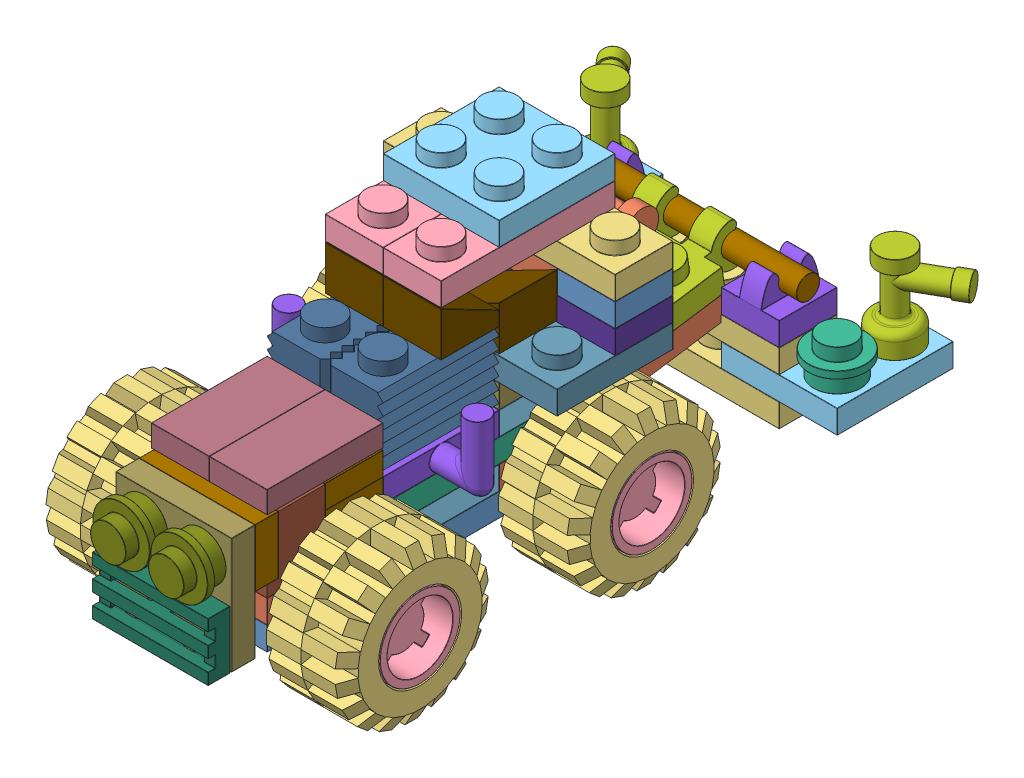
SolidWorks assembly Tractor, configuration Default. Lengths in mm.
Overall size (55.77 47.68 92.37).
59 component instances, 27 part files, 133 mates.
Components (placement in the parent):
- 379526-2: 379526 [Default] at (-1.8667 0.3637 29.8115) size (15.92 5.02 47.76)
- Wheel Assembly-3: Wheel Assembly [Default] at (5.4524 4.3288 25.4431) size (42 29.52 29.52)
  - 4211504-1: 4211504 [Default] at (-7.319 -0.7451 4.3684) size (27.68 6.09 15.92)
  - 4514560-1: 4514560 [Default] at (-18.469 0.3282 0.3884) x (1 0 0) z (0 -0.782052 0.623213) size (11.74 21 21)
  - 4514560-2: 4514560 [Default] at (11.791 0.3282 0.3884) size (11.74 21 21)
  - 4170457-1: 4170457 [Default] at (-12.499 0.3282 0.3884) x (0 1 0) z (0 0 1) size (11 11.84 11)
  - 4170457-2: 4170457 [Default] at (5.821 0.3282 0.3884) x (0 -1 0) z (0 0 1) size (11 11.84 11)
- Wheel Assembly-4: Wheel Assembly [Default] at (5.4524 4.3288 -6.3969) size (42 29.52 29.52)
  - 4211504-1: 4211504 [Default] at (-7.319 -0.7451 4.3684) size (27.68 6.09 15.92)
  - 4514560-1: 4514560 [Default] at (-18.469 0.3282 0.3884) x (1 0 0) z (0 -0.782052 0.623213) size (11.74 21 21)
  - 4514560-2: 4514560 [Default] at (11.791 0.3282 0.3884) size (11.74 21 21)
  - 4170457-1: 4170457 [Default] at (-12.499 0.3282 0.3884) x (0 1 0) z (0 0 1) size (11 11.84 11)
  - 4170457-2: 4170457 [Default] at (5.821 0.3282 0.3884) x (0 -1 0) z (0 0 1) size (11 11.84 11)
- 302224-4: 302224 [Default] at (-1.8667 3.5837 13.8915) size (15.92 5.02 15.92)
- 302024-2: 302024 [Default] at (6.0933 6.8037 21.8515) x (0 0 -1) z (1 0 0) size (31.84 5.02 15.92)
- 4519849-1: 4519849 [Default] at (6.0933 6.8037 -9.9885) x (-1 0 0) z (0 0 -1) size (15.92 6 12.56)
- 302224-5: 302224 [Default] at (-1.8667 10.0237 -2.0285) size (15.92 5.02 15.92)
- 4501109-1: 4501109 [Default] at (6.0933 10.0237 13.8915) x (0 0 -1) z (1 0 0) size (15.92 9.46 14.57)
- 4501109-2: 4501109 [Default] at (-1.8667 10.0237 5.9315) x (0 0 1) z (-1 0 0) size (15.92 9.46 14.57)
- 302326-5: 302326 [Default] at (-1.8667 10.0237 21.8515) size (15.92 5.02 7.96)
- 302326-6: 302326 [Default] at (-1.8667 13.2437 21.8515) size (15.92 5.02 7.96)
- 287724-3: 287724 [Default] at (6.0933 13.2437 13.8915) x (0 0 -1) z (1 0 0) size (15.92 11.5 7.96)
- 287724-4: 287724 [Default] at (-1.8667 13.2437 5.9315) x (0 0 1) z (-1 0 0) size (15.92 11.5 7.96)
- 407026-3: 407026 [Default] at (-1.8667 6.8037 29.8115) x (0 0 -1) z (1 0 0) size (7.96 11.34 7.96)
- 407026-4: 407026 [Default] at (6.0933 6.8037 29.8115) x (0 0 -1) z (1 0 0) size (7.96 11.34 7.96)
- 4211094-2: 4211094 [Default] at (-1.8667 13.2437 -2.0285) size (15.92 5.02 15.92)
- 302326-7: 302326 [Default] at (-1.8667 12.3637 32.2365) x (1 0 0) z (0 -1 0) size (15.92 5.02 7.96)
- 306924-3: 306924 [Default] at (-1.8667 16.4637 29.8115) x (0 0 -1) z (1 0 0) size (15.92 3.22 7.96)
- 306924-4: 306924 [Default] at (6.0933 16.4637 29.8115) x (0 0 -1) z (1 0 0) size (15.92 3.22 7.96)
- 4211065-2: 4211065 [Default] at (-9.8267 16.4637 -2.0285) size (31.84 5.02 15.92)
- 4211094-3: 4211094 [Default] at (-1.8667 4.4037 35.4565) x (1 0 0) z (0 -1 0) size (15.92 5.02 15.92)
- 4211350-3: 4211350 [Default] at (-1.8667 4.4037 38.6765) x (1 0 0) z (0 -1 0) size (15.92 3.22 7.96)
- 3005744-3: 3005744 [Default] at (-1.8667 12.3637 38.6765) x (1 0 0) z (0 -1 0) size (7.8 5.02 7.8)
- 3005744-4: 3005744 [Default] at (6.0933 12.3637 38.6765) x (1 0 0) z (0 -1 0) size (7.8 5.02 7.8)
- 371024-2: 371024 [Default] at (-9.8267 19.6837 -9.9885) size (31.84 5.02 7.96)
- 4244368-3: 4244368 [Default] at (-1.8667 19.6837 -2.0285) x (0 0 -1) z (1 0 0) size (7.96 6.27 7.96)
- 4244368-4: 4244368 [Default] at (6.0933 19.6837 -2.0285) x (0 0 1) z (-1 0 0) size (7.96 6.27 7.96)
- 3000841-1: 3000841 [Default] at (14.0533 22.9037 -9.9885) size (7.96 5.02 7.96)
- 3000841-2: 3000841 [Default] at (-9.8267 22.9037 -9.9885) size (7.96 5.02 7.96)
- 4244627-2: 4244627 [Default] at (6.0933 22.9037 -9.9885) x (-1 0 0) z (0 0 -1) size (15.92 5.02 13.96)
- 4211001-3: 4211001 [Default] at (-9.8267 26.1237 -9.9885) size (31.84 5.02 7.96)
- 4244368-5: 4244368 [Default] at (-1.8667 22.9437 5.9315) x (-1 0 0) z (0 0 -1) size (7.96 6.27 7.96)
- 4244368-6: 4244368 [Default] at (6.0933 22.9437 5.9315) x (-1 0 0) z (0 0 -1) size (7.96 6.27 7.96)
- 362324-2: 362324 [Default] at (-1.8667 29.3437 5.9315) x (0 0 -1) z (1 0 0) size (23.88 5.02 7.96)
- 362324-3: 362324 [Default] at (6.0933 29.3437 5.9315) x (0 0 -1) z (1 0 0) size (23.88 5.02 7.96)
- 302224-6: 302224 [Default] at (-1.8667 32.5637 -2.0285) size (15.92 5.02 15.92)
- 4244627-3: 4244627 [Default] at (-1.8667 7.9827 -25.6977) x (1 0 0) z (0 -0.149253 0.988799) size (15.92 5.02 13.96)
- 4519849-2: 4519849 [Default] at (6.0933 11.1666 -25.2171) x (-1 0 0) z (0 0.149253 -0.988799) size (15.92 6 12.56)
- 4211001-4: 4211001 [Default] at (-9.8267 -0.2849 -32.5247) size (31.84 5.02 7.96)
- 4210635-1: 4210635 [Default] at (-17.7867 2.9351 -32.5247) size (15.92 5.02 15.92)
- 4210635-2: 4210635 [Default] at (22.0133 2.9351 -32.5247) x (0 0 -1) z (1 0 0) size (15.92 5.02 15.92)
- 4211001-5: 4211001 [Default] at (-9.8267 6.1551 -32.5247) size (31.84 5.02 7.96)
- 4211525-1: 4211525 [Default] at (-17.7867 6.1551 -32.5247) size (7.8 5.02 7.8)
- 4211525-2: 4211525 [Default] at (22.0133 6.1551 -32.5247) size (7.8 5.02 7.8)
- 4211503-1: 4211503 [Default] at (-17.7867 6.1551 -40.4847) x (-0.778107 0 0.628132) z (-0.628132 0 -0.778107) size (6.5 11.42 11.15)
- 4211503-2: 4211503 [Default] at (22.0133 6.1551 -40.4847) x (-0.494005 0 -0.869459) z (0.869459 0 -0.494005) size (6.5 11.42 11.15)
- 4211069-1: 4211069 [Default] at (14.0533 9.3751 -32.5247) x (0 0 1) z (-1 0 0) size (8.47 6.96 7.96)
- 4211069-2: 4211069 [Default] at (-9.8267 9.3751 -32.5247) x (0 0 1) z (-1 0 0) size (8.47 6.96 7.96)
- 4211628-1: 4211628 [Default] at (18.0333 14.5451 -32.5247) x (0 1 0) z (0 0 1) size (3.2 32.1 3.2)
Mates (geometry in assembly coordinates):
- Concentric5: concentric aligned: cylinder of 379526-2; cylinder of Wheel Assembly-4/4211504-1
- Concentric6: concentric aligned: cylinder of 379526-2; cylinder of Wheel Assembly-4/4211504-1
- Concentric7: concentric aligned: cylinder of 379526-2; cylinder of Wheel Assembly-3/4211504-1
- Concentric8: concentric aligned: cylinder of 379526-2; cylinder of Wheel Assembly-3/4211504-1
- Coincident3: coincident anti-aligned: plane of 379526-2 through (2.1133 3.5837 33.7915) normal (0 1 0); plane of Wheel Assembly-3/4211504-1 through (2.1133 3.5837 33.7915) normal (0 -1 0)
- Coincident4: coincident anti-aligned: plane of 379526-2 through (2.1133 3.5837 33.7915) normal (0 1 0); plane of Wheel Assembly-4/4211504-1 through (2.1133 3.5837 1.9515) normal (0 -1 0)
- Concentric9: concentric aligned: cylinder of 379526-2; cylinder of 302224-4
- Concentric10: concentric aligned: cylinder of 379526-2; cylinder of 302224-4
- Coincident5: coincident anti-aligned: plane of 379526-2 through (2.1133 3.5837 33.7915) normal (0 1 0); plane of 302224-4 through (2.1133 3.5837 17.8715) normal (0 -1 0)
- Concentric11: concentric aligned: cylinder of Wheel Assembly-4/4211504-1; cylinder of 302024-2
- Concentric12: concentric aligned: cylinder of Wheel Assembly-3/4211504-1; cylinder of 302024-2
- Coincident6: coincident anti-aligned: plane of Wheel Assembly-3/4211504-1 through (2.1133 6.8037 33.7915) normal (0 1 0); plane of 302024-2 through (10.0733 6.8037 17.8715) normal (0 -1 0)
- Concentric13: concentric aligned: cylinder of Wheel Assembly-4/4211504-1; cylinder of 4519849-1
- Concentric14: concentric aligned: cylinder of Wheel Assembly-4/4211504-1; cylinder of 4519849-1
- Coincident7: coincident anti-aligned: plane of Wheel Assembly-4/4211504-1 through (2.1133 6.8037 1.9515) normal (0 1 0); plane of 4519849-1 through (2.1133 6.8037 -13.9685) normal (0 -1 0)
- Concentric15: concentric aligned: cylinder of 4519849-1; cylinder of 302224-5
- Concentric16: concentric aligned: cylinder of 302024-2; cylinder of 302224-5
- Coincident8: coincident anti-aligned: plane of 302024-2 through (10.0733 10.0237 17.8715) normal (0 1 0); plane of 302224-5 through (2.1133 10.0237 1.9515) normal (0 -1 0)
- Concentric17: concentric aligned: cylinder of 302024-2; cylinder of 4501109-1
- Concentric18: concentric aligned: cylinder of 302024-2; cylinder of 4501109-1
- Coincident9: coincident anti-aligned: plane of 302024-2 through (10.0733 10.0237 17.8715) normal (0 1 0); plane of 4501109-1 through (10.0733 10.0237 9.9115) normal (0 -1 0)
- Concentric19: concentric aligned: cylinder of 302024-2; cylinder of 4501109-2
- Concentric20: concentric aligned: cylinder of 302024-2; cylinder of 4501109-2
- Coincident10: coincident anti-aligned: plane of 302024-2 through (10.0733 10.0237 17.8715) normal (0 1 0); plane of 4501109-2 through (-5.8467 10.0237 9.9115) normal (0 -1 0)
- Concentric21: concentric aligned: cylinder of 302024-2; cylinder of 302326-5
- Concentric22: concentric aligned: cylinder of 302024-2; cylinder of 302326-5
- Coincident11: coincident anti-aligned: plane of 302024-2 through (10.0733 10.0237 17.8715) normal (0 1 0); plane of 302326-5 through (2.1133 10.0237 25.8315) normal (0 -1 0)
- Concentric23: concentric aligned: cylinder of 302326-5; cylinder of 302326-6
- Concentric24: concentric aligned: cylinder of 302326-5; cylinder of 302326-6
- Coincident12: coincident anti-aligned: plane of 302326-5 through (2.1133 13.2437 25.8315) normal (0 1 0); plane of 302326-6 through (2.1133 13.2437 25.8315) normal (0 -1 0)
- Concentric25: concentric aligned: cylinder of 4501109-1; cylinder of 287724-3
- Concentric26: concentric aligned: cylinder of 4501109-1; cylinder of 287724-3
- Coincident13: coincident anti-aligned: plane of 4501109-1 through (10.0733 13.2437 9.9115) normal (0 1 0); plane of 287724-3 through (10.0733 13.2437 9.9115) normal (0 -1 0)
- Concentric27: concentric aligned: cylinder of 4501109-2; cylinder of 287724-4
- Concentric28: concentric aligned: cylinder of 4501109-2; cylinder of 287724-4
- Coincident14: coincident anti-aligned: plane of 4501109-2 through (-5.8467 13.2437 9.9115) normal (0 1 0); plane of 287724-4 through (-5.8467 13.2437 9.9115) normal (0 -1 0)
- Coincident15: coincident anti-aligned: plane of Wheel Assembly-3/4211504-1 through (2.1133 6.8037 33.7915) normal (0 1 0); plane of 407026-3 through (2.1133 6.8037 25.8315) normal (0 -1 0)
- Coincident16: coincident aligned: plane of Wheel Assembly-3/4211504-1 through (-5.8467 6.8037 25.8315) normal (-1 0 0); plane of 407026-3 through (-5.8467 16.3437 33.7915) normal (-1 0 0)
- Concentric29: concentric aligned: cylinder of Wheel Assembly-3/4211504-1; cylinder of 407026-3
- Concentric30: concentric aligned: cylinder of Wheel Assembly-3/4211504-1; cylinder of 407026-4
- Coincident17: coincident anti-aligned: plane of 407026-3 through (2.1133 16.3437 33.7915) normal (1 0 0); plane of 407026-4 through (2.1133 16.3437 33.7915) normal (-1 0 0)
- Coincident18: coincident anti-aligned: plane of Wheel Assembly-3/4211504-1 through (2.1133 6.8037 33.7915) normal (0 1 0); plane of 407026-4 through (10.0733 6.8037 25.8315) normal (0 -1 0)
- Concentric31: concentric aligned: cylinder of 302224-5; cylinder of 4211094-2
- Concentric32: concentric aligned: cylinder of 302224-5; cylinder of 4211094-2
- Coincident19: coincident anti-aligned: plane of 302224-5 through (2.1133 13.2437 1.9515) normal (0 1 0); plane of 4211094-2 through (2.1133 13.2437 1.9515) normal (0 -1 0)
- Concentric33: concentric aligned: cylinder of 302326-7; cylinder of 407026-4
- Concentric34: concentric aligned: cylinder of 407026-3; cylinder of 302326-7
- Coincident20: coincident anti-aligned: plane of 407026-4 through (2.1133 8.4037 32.2365) normal (0 0 1); plane of 302326-7 through (2.1133 8.3837 32.2365) normal (0 0 -1)
- Coincident21: coincident anti-aligned: plane of 287724-4 through (2.1133 22.9437 17.8715) normal (0 0 1); plane of 306924-3 through (-5.8467 19.6837 17.8715) normal (0 0 -1)
- Coincident22: coincident anti-aligned: plane of 302326-6 through (2.1133 16.4637 25.8315) normal (0 1 0); plane of 306924-3 through (2.1133 16.4637 25.8315) normal (0 -1 0)
- Coincident23: coincident aligned: plane of 302326-6 through (-5.8467 16.4637 17.8715) normal (-1 0 0); plane of 306924-3 through (-5.8467 19.6837 33.7915) normal (-1 0 0)
- Concentric35: concentric aligned: cylinder of 4211094-2; cylinder of 4211065-2
- Concentric36: concentric aligned: cylinder of 4211094-2; cylinder of 4211065-2
- Coincident24: coincident anti-aligned: plane of 4211094-2 through (2.1133 16.4637 1.9515) normal (0 1 0); plane of 4211065-2 through (-5.8467 16.4637 1.9515) normal (0 -1 0)
- Coincident25: coincident aligned: plane of 4211094-3 through (10.0733 8.3837 38.6765) normal (1 0 0); plane of 4211350-3 through (10.0733 8.3837 41.8965) normal (1 0 0)
- Coincident26: coincident aligned: plane of 4211094-3 through (-5.8467 0.4237 38.6765) normal (0 -1 0); plane of 4211350-3 through (-5.8467 0.4237 41.8965) normal (0 -1 0)
- Coincident27: coincident anti-aligned: plane of 4211094-3 through (2.1133 0.4237 38.6765) normal (0 0 1); plane of 4211350-3 through (2.1133 0.4237 38.6765) normal (0 0 -1)
- Concentric37: concentric aligned: cylinder of 4211094-3; cylinder of 3005744-3
- Coincident28: coincident anti-aligned: plane of 4211094-3 through (2.1133 0.4237 38.6765) normal (0 0 1); plane of 3005744-3 through (-1.8667 12.3637 38.6765) normal (0 0 -1)
- Concentric38: concentric aligned: cylinder of 4211094-3; cylinder of 3005744-4
- Coincident29: coincident anti-aligned: plane of 4211094-3 through (2.1133 0.4237 38.6765) normal (0 0 1); plane of 3005744-4 through (6.0933 12.3637 38.6765) normal (0 0 -1)
- Coincident30: coincident aligned: plane of 302326-7 through (10.0733 16.3437 35.4565) normal (1 0 0); plane of 4211094-3 through (10.0733 8.3837 38.6765) normal (1 0 0)
- Coincident31: coincident aligned: plane of 4211094-3 through (-5.8467 16.3437 38.6765) normal (0 1 0); plane of 302326-7 through (-5.8467 16.3437 35.4565) normal (0 1 0)
- Coincident32: coincident anti-aligned: plane of 302326-7 through (2.1133 8.3837 35.4565) normal (0 0 1); plane of 4211094-3 through (2.1133 0.4237 35.4565) normal (0 0 -1)
- Concentric39: concentric aligned: cylinder of 4211065-2; cylinder of 371024-2
- Concentric40: concentric aligned: cylinder of 4211065-2; cylinder of 371024-2
- Coincident33: coincident anti-aligned: plane of 4211065-2 through (-5.8467 19.6837 1.9515) normal (0 1 0); plane of 371024-2 through (-5.8467 19.6837 -6.0085) normal (0 -1 0)
- Coincident34: coincident anti-aligned: plane of 4244368-3 through (2.1133 25.9837 1.9515) normal (1 0 0); plane of 4244368-4 through (2.1133 25.9837 -6.0085) normal (-1 0 0)
- Coincident35: coincident aligned: plane of 4244368-3 through (2.1133 19.6837 -6.0085) normal (0 -1 0); plane of 4244368-4 through (2.1133 19.6837 1.9515) normal (0 -1 0)
- Coincident36: coincident aligned: plane of 4244368-3 through (-5.8467 25.9837 1.9515) normal (0 0 1); plane of 4244368-4 through (10.0733 25.9837 1.9515) normal (0 0 1)
- Coincident37: coincident aligned: plane of 4211065-2 through (-13.8067 19.6837 1.9515) normal (0 0 1); plane of 4244368-4 through (10.0733 25.9837 1.9515) normal (0 0 1)
- Distance1: distance = 7.96 mm aligned: plane of 4211065-2 through (-13.8067 19.6837 -6.0085) normal (-1 0 0); plane of 4244368-3 through (-5.8467 25.9837 1.9515) normal (-1 0 0)
- Coincident39: coincident anti-aligned: plane of 4211065-2 through (-5.8467 19.6837 1.9515) normal (0 1 0); plane of 4244368-3 through (2.1133 19.6837 -6.0085) normal (0 -1 0)
- Coincident40: coincident aligned: plane of 371024-2 through (18.0333 22.9037 -13.9685) normal (1 0 0); plane of 3000841-1 through (18.0333 26.1237 -13.9685) normal (1 0 0)
- Coincident42: coincident aligned: plane of 371024-2 through (-13.8067 22.9037 -13.9685) normal (0 0 -1); plane of 3000841-1 through (10.0733 26.1237 -13.9685) normal (0 0 -1)
- Coincident43: coincident anti-aligned: plane of 371024-2 through (-5.8467 22.9037 -6.0085) normal (0 1 0); plane of 3000841-1 through (18.0333 22.9037 -6.0085) normal (0 -1 0)
- Coincident44: coincident aligned: plane of 371024-2 through (-13.8067 22.9037 -13.9685) normal (0 0 -1); plane of 3000841-2 through (-13.8067 26.1237 -13.9685) normal (0 0 -1)
- Coincident45: coincident anti-aligned: plane of 371024-2 through (-5.8467 22.9037 -6.0085) normal (0 1 0); plane of 3000841-2 through (-5.8467 22.9037 -6.0085) normal (0 -1 0)
- Coincident46: coincident aligned: plane of 371024-2 through (-13.8067 22.9037 -13.9685) normal (-1 0 0); plane of 3000841-2 through (-13.8067 26.1237 -13.9685) normal (-1 0 0)
- Concentric41: concentric aligned: cylinder of 371024-2; cylinder of 4244627-2
- Concentric42: concentric aligned: cylinder of 371024-2; cylinder of 4244627-2
- Coincident47: coincident anti-aligned: plane of 371024-2 through (-5.8467 22.9037 -6.0085) normal (0 1 0); plane of 4244627-2 through (2.1133 22.9037 -13.9685) normal (0 -1 0)
- Concentric43: concentric aligned: cylinder of 3000841-2; cylinder of 4211001-3
- Concentric44: concentric aligned: cylinder of 3000841-1; cylinder of 4211001-3
- Coincident48: coincident anti-aligned: plane of 4244627-2 through (2.1133 26.1237 -13.9685) normal (0 1 0); plane of 4211001-3 through (-5.8467 26.1237 -6.0085) normal (0 -1 0)
- Coincident50: coincident anti-aligned: plane of 4244368-5 through (2.1133 29.2437 9.9115) normal (1 0 0); plane of 4244368-6 through (2.1133 29.2437 9.9115) normal (-1 0 0)
- Coincident51: coincident aligned: plane of 4244368-5 through (2.1133 29.2437 9.9115) normal (0 0 1); plane of 4244368-6 through (10.0733 29.2437 9.9115) normal (0 0 1)
- Coincident56: coincident aligned: plane of 4244368-5 through (-5.8467 22.9437 1.9515) normal (0 -1 0); plane of 4244368-6 through (2.1133 22.9437 1.9515) normal (0 -1 0)
- Coincident57: coincident aligned: plane of 4244368-5 through (2.1133 29.2437 1.9515) normal (0 0 -1); plane of 287724-4 through (2.1133 22.9437 1.9515) normal (0 0 -1)
- Coincident58: coincident anti-aligned: plane of 287724-3 through (10.0733 22.9437 9.9115) normal (0 1 0); plane of 4244368-6 through (2.1133 22.9437 1.9515) normal (0 -1 0)
- Coincident59: coincident aligned: plane of 4244368-4 through (10.0733 25.9837 -6.0085) normal (1 0 0); plane of 4244368-6 through (10.0733 29.2437 9.9115) normal (1 0 0)
- Concentric45: concentric aligned: cylinder of 4211001-3; cylinder of 362324-2
- Coincident60: coincident aligned: plane of 4211001-3 through (-13.8067 29.3437 -13.9685) normal (0 0 -1); plane of 362324-2 through (-5.8467 32.5637 -13.9685) normal (0 0 -1)
- Coincident61: coincident anti-aligned: plane of 4211001-3 through (-5.8467 29.3437 -6.0085) normal (0 1 0); plane of 362324-2 through (2.1133 29.3437 1.9515) normal (0 -1 0)
- Concentric46: concentric aligned: cylinder of 4211001-3; cylinder of 362324-3
- Coincident62: coincident aligned: plane of 4211001-3 through (-13.8067 29.3437 -13.9685) normal (0 0 -1); plane of 362324-3 through (2.1133 32.5637 -13.9685) normal (0 0 -1)
- Coincident63: coincident anti-aligned: plane of 4211001-3 through (-5.8467 29.3437 -6.0085) normal (0 1 0); plane of 362324-3 through (10.0733 29.3437 1.9515) normal (0 -1 0)
- Concentric47: concentric aligned: cylinder of 362324-2; cylinder of 302224-6
- Concentric48: concentric aligned: cylinder of 362324-3; cylinder of 302224-6
- Coincident64: coincident anti-aligned: plane of 362324-3 through (10.0733 32.5637 1.9515) normal (0 1 0); plane of 302224-6 through (2.1133 32.5637 1.9515) normal (0 -1 0)
- Concentric49: concentric aligned: cylinder of 4519849-1; cylinder of 4244627-3
- Coincident65: coincident aligned: plane of 4519849-1 through (10.0733 10.0237 -6.0085) normal (1 0 0); plane of 4244627-3 through (10.0733 11.7606 -29.1526) normal (1 0 0)
- Concentric51: concentric aligned: cylinder of 4244627-3; cylinder of 4519849-2
- Concentric52: concentric aligned: cylinder of 4244627-3; cylinder of 4519849-2
- Coincident66: coincident anti-aligned: plane of 4244627-3 through (2.1133 10.5726 -21.2817) normal (0 0.988799 0.149253); plane of 4519849-2 through (2.1133 11.7606 -29.1526) normal (0 -0.988799 -0.149253)
- Concentric53: concentric aligned: cylinder of 4211001-4; cylinder of 4210635-2
- Coincident67: coincident anti-aligned: plane of 4211001-4 through (-5.8467 2.9351 -28.5447) normal (0 1 0); plane of 4210635-2 through (25.9933 2.9351 -36.5047) normal (0 -1 0)
- Coincident68: coincident aligned: plane of 4211001-4 through (-13.8067 2.9351 -28.5447) normal (0 0 1); plane of 4210635-2 through (18.0333 6.1551 -28.5447) normal (0 0 1)
- Coincident69: coincident aligned: plane of 4211001-4 through (-13.8067 2.9351 -28.5447) normal (0 0 1); plane of 4210635-1 through (-21.7667 6.1551 -28.5447) normal (0 0 1)
- Concentric55: concentric aligned: cylinder of 4211001-4; cylinder of 4210635-1
- Coincident71: coincident anti-aligned: plane of 4211001-4 through (-5.8467 2.9351 -28.5447) normal (0 1 0); plane of 4210635-1 through (-13.8067 2.9351 -28.5447) normal (0 -1 0)
- Concentric56: concentric aligned: cylinder of 4210635-1; cylinder of 4211001-5
- Concentric57: concentric aligned: cylinder of 4210635-2; cylinder of 4211001-5
- Coincident73: coincident anti-aligned: plane of 4210635-2 through (25.9933 6.1551 -36.5047) normal (0 1 0); plane of 4211001-5 through (-5.8467 6.1551 -28.5447) normal (0 -1 0)
- Concentric58: concentric aligned: cylinder of 4210635-1; cylinder of 4211525-1
- Coincident74: coincident anti-aligned: plane of 4210635-1 through (-13.8067 6.1551 -28.5447) normal (0 1 0); plane of 4211525-1 through (-17.7867 6.1551 -32.5247) normal (0 -1 0)
- Concentric59: concentric aligned: cylinder of 4210635-2; cylinder of 4211525-2
- Coincident75: coincident anti-aligned: plane of 4210635-2 through (25.9933 6.1551 -36.5047) normal (0 1 0); plane of 4211525-2 through (22.0133 6.1551 -32.5247) normal (0 -1 0)
- Concentric60: concentric aligned: cylinder of 4210635-1; cylinder of 4211503-1
- Coincident76: coincident anti-aligned: plane of 4210635-1 through (-13.8067 6.1551 -28.5447) normal (0 1 0); plane of 4211503-1 through (-17.7867 6.1551 -40.4847) normal (0 -1 0)
- Concentric61: concentric aligned: cylinder of 4210635-2; cylinder of 4211503-2
- Coincident77: coincident anti-aligned: plane of 4210635-2 through (25.9933 6.1551 -36.5047) normal (0 1 0); plane of 4211503-2 through (22.0133 6.1551 -40.4847) normal (0 -1 0)
- Coincident78: coincident aligned: plane of 4211069-1 through (18.0333 12.5951 -28.5447) normal (0 0 1); plane of 4211001-5 through (-13.8067 9.3751 -28.5447) normal (0 0 1)
- Coincident79: coincident aligned: plane of 4211069-2 through (-5.8467 12.5951 -28.5447) normal (0 0 1); plane of 4211001-5 through (-13.8067 9.3751 -28.5447) normal (0 0 1)
- Coincident80: coincident aligned: plane of 4211001-5 through (18.0333 9.3751 -36.5047) normal (1 0 0); plane of 4211069-1 through (18.0333 12.5951 -36.5047) normal (1 0 0)
- Coincident81: coincident aligned: plane of 4211001-5 through (-13.8067 9.3751 -36.5047) normal (-1 0 0); plane of 4211069-2 through (-13.8067 12.5951 -36.5047) normal (-1 0 0)
- Coincident82: coincident anti-aligned: plane of 4211001-5 through (-5.8467 9.3751 -28.5447) normal (0 1 0); plane of 4211069-1 through (10.0733 9.3751 -28.5447) normal (0 -1 0)
- Coincident83: coincident anti-aligned: plane of 4211001-5 through (-5.8467 9.3751 -28.5447) normal (0 1 0); plane of 4211069-2 through (-13.8067 9.3751 -28.5447) normal (0 -1 0)
- Concentric62: concentric anti-aligned: cylinder of 4211069-1; cylinder of 4211628-1
- Coincident84: coincident aligned: plane of 4211069-1 through (18.0333 12.5951 -36.5047) normal (1 0 0); plane of 4211628-1 through (18.0333 14.5451 -32.5247) normal (1 0 0)
- Concentric63: concentric anti-aligned: cylinder of 4519849-2; cylinder of 4211628-1
- Coincident85: coincident aligned: plane of 4211065-2 through (18.0333 19.6837 -6.0085) normal (1 0 0); plane of 4211001-5 through (18.0333 9.3751 -36.5047) normal (1 0 0)
- Parallel1: parallel aligned: unknown of 379526-2; unknown of 4211001-4
